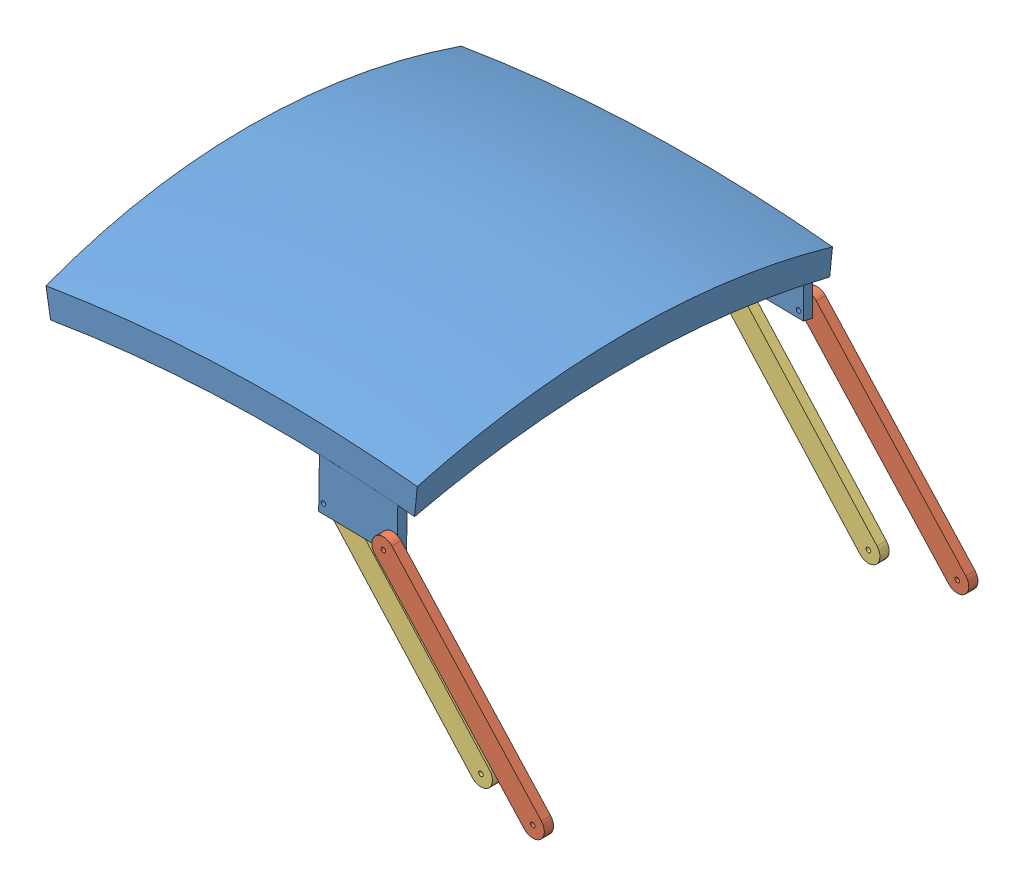
SolidWorks assembly Roof Assembly, configuration Default. Lengths in mm.
Overall size (1124.96 1284.64 940).
5 component instances, 3 part files, 11 mates.
Components (placement in the parent):
- Roof  2021-1: Roof  2021 [Default] at (594.3152 459.0763 929.0689) x (0.999884 -0.015247 0) z (0 0 1) size (823.23 903.61 900)
- Rear Rocker-1: Rear Rocker [Default] at (712.7372 113.3021 963.8006) x (0.737782 0.675039 0) z (0 0 1) size (50 530 20)
- Front Rocker-1: Front Rocker [Default] at (685.2384 -97.3864 923.8006) x (0.742546 0.669795 0) z (0 0 1) size (50 530 20)
- Rear Rocker-2: Rear Rocker [Default] at (712.7372 113.3021 43.8006) x (0.737782 0.675039 0) z (0 0 1) size (50 530 20)
- Front Rocker-2: Front Rocker [Default] at (685.2384 -97.3864 83.8006) x (0.742546 0.669795 0) z (0 0 1) size (50 530 20)
Mates (geometry in assembly coordinates):
- Concentric2: concentric aligned: cylinder of Roof  2021-1 through (532.2832 273.4938 963.8006) axis (0 0 1) radius 5; cylinder of Rear Rocker-1 through (532.2832 273.4938 983.8006) axis (0 0 1) radius 5
- Coincident2: coincident anti-aligned: plane of Rear Rocker-1 through (856.3021 -80.6415 963.8006) normal (0 0 -1); plane of Roof  2021-1 through (278.525 -2592.3859 963.8006) normal (0 0 1)
- Concentric4: concentric aligned: cylinder of Roof  2021-1 through (382.3006 275.7808 963.8006) axis (0 0 1) radius 5; cylinder of Front Rocker-1 through (382.3006 275.7808 943.8006) axis (0 0 1) radius 5
- Concentric6: concentric aligned: cylinder of Roof  2021-1 through (532.2832 273.4938 963.8006) axis (0 0 1) radius 5; cylinder of Rear Rocker-2 through (532.2832 273.4938 63.8006) axis (0 0 1) radius 5
- Concentric8: concentric aligned: cylinder of Roof  2021-1 through (382.3006 275.7808 963.8006) axis (0 0 1) radius 5; cylinder of Front Rocker-2 through (382.3006 275.7808 103.8006) axis (0 0 1) radius 5
- Coincident3: coincident anti-aligned: plane of Roof  2021-1 through (1439.2495 -2244.3652 891.6032) normal (0 0 1); plane of Front Rocker-1 through (721.5992 363.7757 891.6032) normal (0 0 -1)
- Coincident4: coincident anti-aligned: plane of Roof  2021-1 through (1439.2495 -2244.3652 -8.3968) normal (0 0 -1); plane of Rear Rocker-2 through (870.382 382.8459 -8.3968) normal (0 0 1)
- Coincident5: coincident anti-aligned: plane of Roof  2021-1 through (1439.2495 -2244.3652 -8.3968) normal (0 0 -1); plane of Front Rocker-2 through (721.5992 363.7757 -8.3968) normal (0 0 1)
- Coincident6: coincident anti-aligned: plane of Roof  2021-1 through (235.7609 -3084.3476 943.8006) normal (0 0 -1); plane of Front Rocker-1 through (703.8021 -80.6415 943.8006) normal (0 0 1)
- Coincident7: coincident anti-aligned: plane of Roof  2021-1 through (235.7609 -3084.3476 83.8006) normal (0 0 1); plane of Front Rocker-2 through (703.8021 -80.6415 83.8006) normal (0 0 -1)
- Coincident8: coincident anti-aligned: plane of Roof  2021-1 through (278.525 -2592.3859 63.8006) normal (0 0 -1); plane of Rear Rocker-2 through (856.3021 -80.6415 63.8006) normal (0 0 1)
